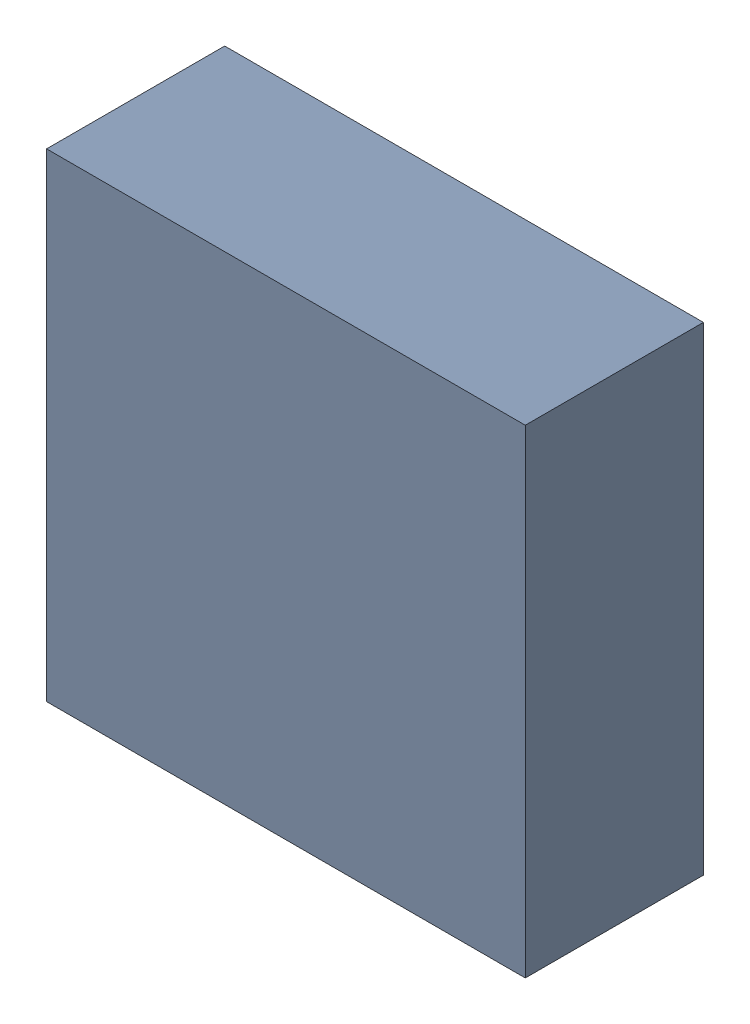
SolidWorks assembly Q3, configuration ﾃﾞﾌｫﾙﾄ. Lengths in mm.
Overall size (2.15 2.15 0.8).
2 component instances, 1 part files, 0 mates.
Components (placement in the parent):
- 689261240-1: 689261240 [ﾃﾞﾌｫﾙﾄ] at (25.5 73.25 0) size (2.15 2.15 0.8)
  - Extruded_30-1: Extruded_30 [ﾃﾞﾌｫﾙﾄ] at origin size (2.15 2.15 0.8)
